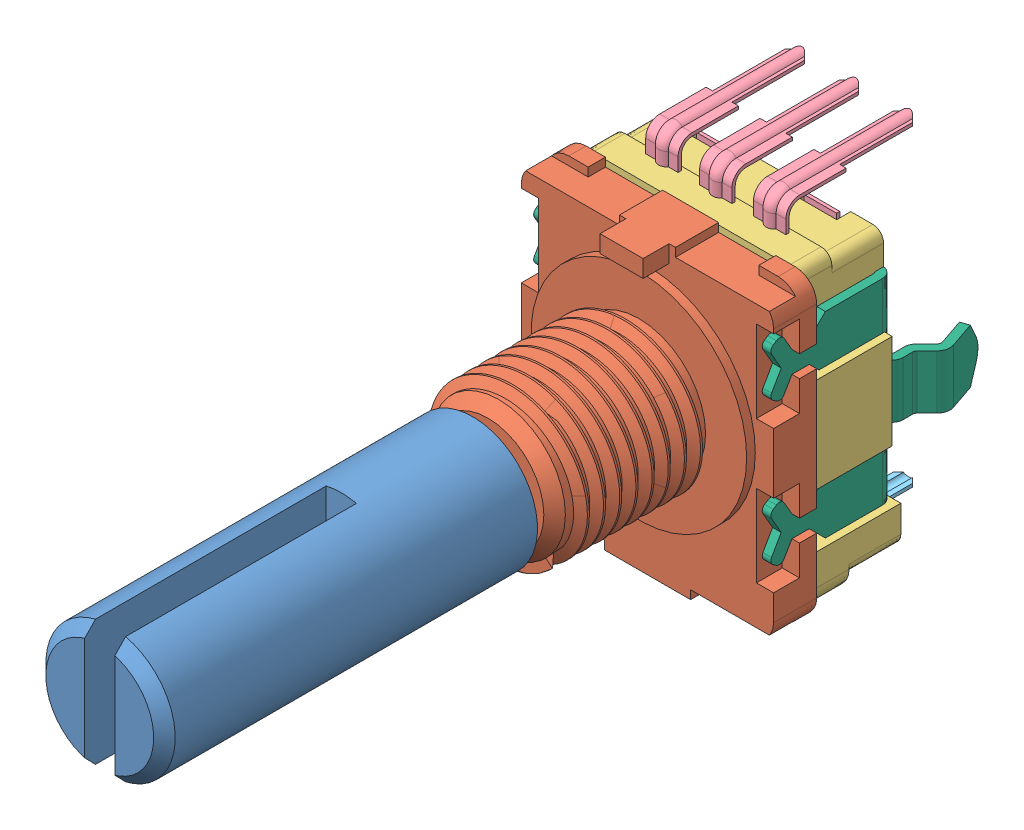
SolidWorks assembly User Library-EC11B15244, configuration Default. Lengths in mm.
Overall size (13.1 15.13 23.87).
10 component instances, 6 part files, 0 mates.
Components (placement in the parent):
- User Library-EC11B15244_Shaft-1: User Library-EC11B15244_Shaft [Default] at (0 0 13.6) size (6 6 6.8)
- User Library-EC11B15244_MetalBody-1: User Library-EC11B15244_MetalBody [Default] at (0 0 3.443) size (11.7 13.8 9.78)
- User Library-EC11B15244_PlasticBody-1: User Library-EC11B15244_PlasticBody [Default] at (-0.85 -0.6436 6.5892) size (11.7 13.3 3.9)
- User Library-EC11B15244_Pins-1: User Library-EC11B15244_Pins [Default] at (0 0 6.6326) size (13.1 14.95 9.45)
  - User Library-EC11B15244_Imported-1: User Library-EC11B15244_Imported [Default] at (-2.5 7.575 -10.2243) x (0 -1 0) z (0 0 1) size (2.34 1.5 6.65)
  - User Library-EC11B15244_Imported-2: User Library-EC11B15244_Imported [Default] at (0 7.575 -10.2243) x (0 -1 0) z (0 0 1) size (2.34 1.5 6.65)
  - User Library-EC11B15244_Imported-3: User Library-EC11B15244_Imported [Default] at (2.5 7.575 -10.2243) x (0 -1 0) z (0 0 1) size (2.34 1.5 6.65)
  - User Library-EC11B15244_Pin-1: User Library-EC11B15244_Pin [Default] at (-2.5 -7.075 -10.2243) x (0 1 0) z (0 0 1) size (2.15 1.5 4.73)
  - User Library-EC11B15244_Pin-2: User Library-EC11B15244_Pin [Default] at (2.5 -7.075 -10.2243) x (0 1 0) z (0 0 1) size (2.15 1.5 4.73)
  - User Library-EC11B15244_Sheet Metal Part53-1: User Library-EC11B15244_Sheet Metal Part53 [Default] at (-24.7094 3.8245 8.4125) size (13.1 9.9 9.18)
